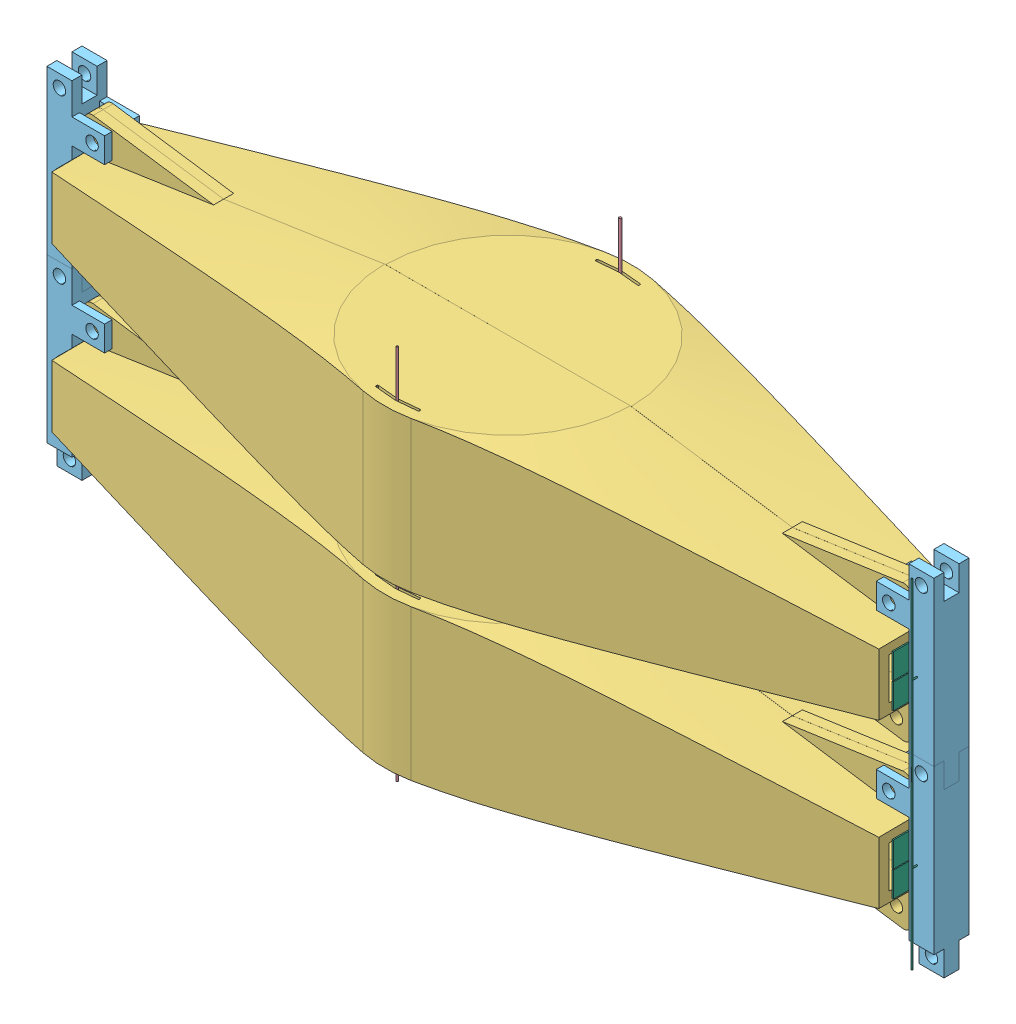
SolidWorks assembly ConnectingDemo, configuration 默认. Lengths in mm.
Overall size (374.87 155.61 350.65).
24 component instances, 6 part files, 2 mates.
Components (placement in the parent):
- RealUnit-1: RealUnit [默认] at (-20.1774 7.1074 294.8665) size (374.87 90.61 350.65)
  - BEGeDet-1: BEGeDet [默认] at (2.9686 -23.0613 80) size (80 40 80)
  - InnerShell-IV-1: InnerShell-IV [默认] at (2.9686 -23.1113 80) x (0.656103 0 0.754671) z (-0.754671 0 0.656103) size (89 50 89)
  - RealOuterShell-IV-Part-3: RealOuterShell-IV-Part [默认] at (2.9686 -24.1113 80) x (-1 0 0) z (0 0 -1) size (357.21 73.56 262.25)
  - RealOuterShell-IV-Part-4: RealOuterShell-IV-Part [默认] at (2.5967 -24.1114 80) x (1 0.000332 0) z (0 0 1) size (357.21 73.56 262.25)
  - Electronics-1: Electronics [默认] at (2.9686 -48.2113 80) x (-1 0 0) z (0 0 -1) size (21.21 85 89.7)
  - ConnectionUnit-1: ConnectionUnit [默认] at (157.8605 -24.8554 155) x (-1 -0.000332 0) z (0 0 -1) size (23 75 26.4)
    - ConnectionRod-IV-1: ConnectionRod-IV [默认] at (-16.742 6.238 75) size (23 75 14)
    - RealSiPMArray-1: RealSiPMArray [默认] at (-11.242 1.238 75) x (-1 0 0) z (0 0 -1) size (3.97 70 26.4)
  - ConnectionUnit-2: ConnectionUnit [默认] at (-152.295 -24.9069 5) size (23 75 26.4)
    - ConnectionRod-IV-1: ConnectionRod-IV [默认] at (-16.742 6.238 75) size (23 75 14)
    - RealSiPMArray-1: RealSiPMArray [默认] at (-11.242 1.238 75) x (-1 0 0) z (0 0 -1) size (3.97 70 26.4)
- RealUnit-3: RealUnit [默认] at (-20.1774 72.1074 294.8665) size (374.87 90.61 350.65)
  - BEGeDet-1: BEGeDet [默认] at (2.9686 -23.0613 80) size (80 40 80)
  - InnerShell-IV-1: InnerShell-IV [默认] at (2.9686 -23.1113 80) x (0.656103 0 0.754671) z (-0.754671 0 0.656103) size (89 50 89)
  - RealOuterShell-IV-Part-3: RealOuterShell-IV-Part [默认] at (2.9686 -24.1113 80) x (-1 0 0) z (0 0 -1) size (357.21 73.56 262.25)
  - RealOuterShell-IV-Part-4: RealOuterShell-IV-Part [默认] at (2.5967 -24.1114 80) x (1 0.000332 0) z (0 0 1) size (357.21 73.56 262.25)
  - Electronics-1: Electronics [默认] at (2.9686 -48.2113 80) x (-1 0 0) z (0 0 -1) size (21.21 85 89.7)
  - ConnectionUnit-1: ConnectionUnit [默认] at (157.8605 -24.8554 155) x (-1 -0.000332 0) z (0 0 -1) size (23 75 26.4)
    - ConnectionRod-IV-1: ConnectionRod-IV [默认] at (-16.742 6.238 75) size (23 75 14)
    - RealSiPMArray-1: RealSiPMArray [默认] at (-11.242 1.238 75) x (-1 0 0) z (0 0 -1) size (3.97 70 26.4)
  - ConnectionUnit-2: ConnectionUnit [默认] at (-152.295 -24.9069 5) size (23 75 26.4)
    - ConnectionRod-IV-1: ConnectionRod-IV [默认] at (-16.742 6.238 75) size (23 75 14)
    - RealSiPMArray-1: RealSiPMArray [默认] at (-11.242 1.238 75) x (-1 0 0) z (0 0 -1) size (3.97 70 26.4)
Mates (geometry in assembly coordinates):
- 重合1: coincident anti-aligned: circle of RealUnit-1/ConnectionUnit-2/ConnectionRod-IV-1; circle of RealUnit-3/ConnectionUnit-2/ConnectionRod-IV-1
- 重合3: coincident aligned: plane of RealUnit-1/ConnectionUnit-2/ConnectionRod-IV-1 through (-194.2144 20.9386 367.8665) normal (-1 0 0); plane of RealUnit-3/ConnectionUnit-2/ConnectionRod-IV-1 through (-194.2144 85.9386 367.8665) normal (-1 0 0)
